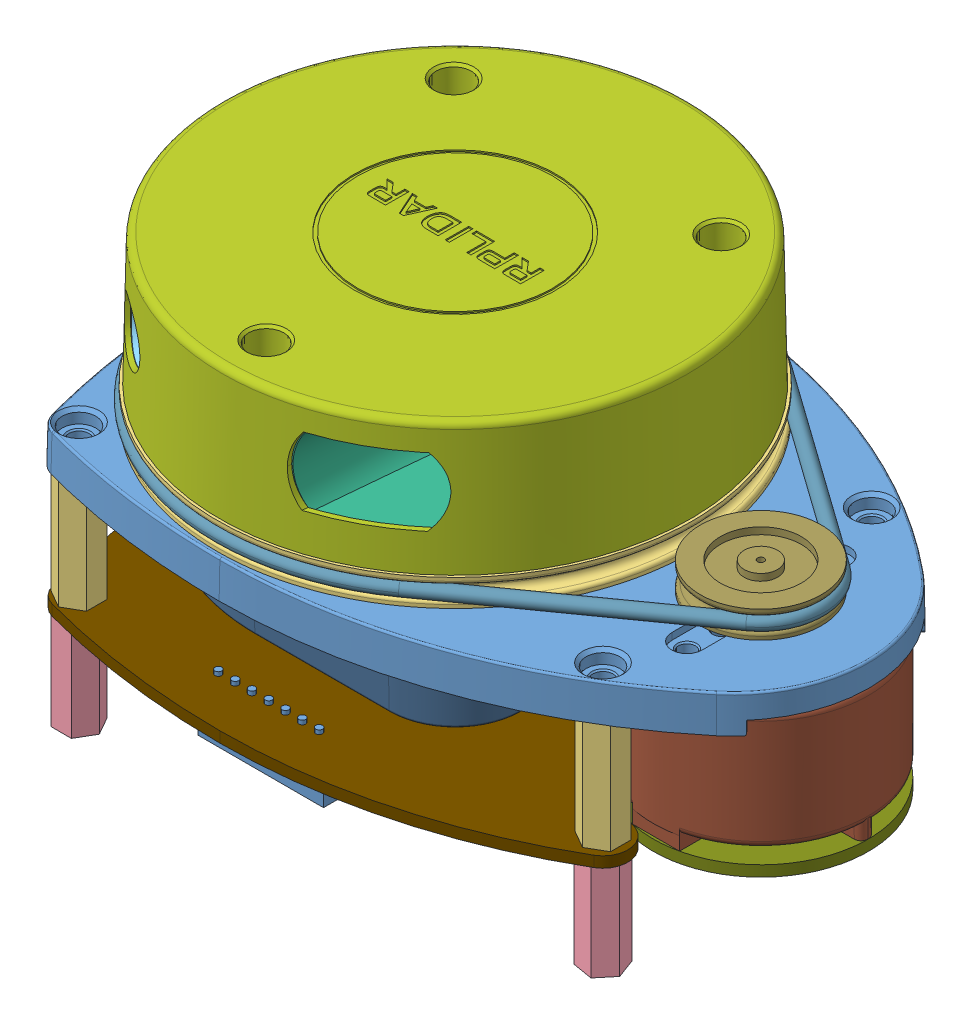
SolidWorks assembly LIDAR, configuration По умолчанию. Lengths in mm.
Overall size (102.81 63.21 71.78).
28 component instances, 22 part files, 30 mates.
Components (placement in the parent):
- 1-1: 1 [По умолчанию] at (-69.4738 21.696 -13.0661) size (96.74 12.71 70.28)
- 2-1: 2 [По умолчанию] at (-69.4738 23.696 -13.0661) x (1 0 0) z (0 -1 0) size (47 47 7.01)
- 3-1: 3 [По умолчанию] at (-69.4738 25.696 -13.0661) x (0.00451 0 -0.99999) z (0.99999 0 0.00451) size (70.79 21.41 70.79)
- 4-1: 4 [По умолчанию] at (-94.6291 38.696 -19.9402) x (0.990886 0 -0.134705) z (0.134705 0 0.990886) size (6.5 6.5 21.2)
- 5-1: 5 [По умолчанию] at (-69.4738 29.696 -13.0661) x (-0.99999 0 -0.00451) z (0.00451 0 -0.99999) size (15.26 18.52 21.56)
- 6-1: 6 [По умолчанию] at (-69.4738 29.696 -13.0661) x (-0.99999 0 -0.00451) z (0.00451 0 -0.99999) size (22.09 18.86 24.76)
- 7-1: 7 [По умолчанию] at (-69.4738 47.696 -13.0661) x (0.99999 0 0.00451) z (0.00451 0 -0.99999) size (70 19.51 70)
- 8-1: 8 [По умолчанию] at (-69.4738 12.696 -13.0661) x (0.987093 0 -0.160146) z (0.160146 0 0.987093) size (25 1.2 25)
- 9-1: 9 [По умолчанию] at (-69.4738 11.696 -13.0661) size (55.5 1 57)
- 10-1: 10 [По умолчанию] at (-69.4738 10.696 -13.0661) size (59.96 11.11 60.96)
- 11-1: 11 [По умолчанию] at (-23.9738 2.196 -13.0661) x (0 0 -1) z (1 0 0) size (32 30.21 32.01)
- 12-1: 12 [По умолчанию] at (-23.9738 24.196 -13.0661) x (0.135455 0 -0.990784) z (0.990784 0 0.135455) size (18 5.5 18)
- 13-1: 13 [По умолчанию] at (-52.5259 38.696 -1.4895) x (0.136926 0.990581 0.000618) z (-0.00451 0 0.99999) size (14 14 11.5)
- 14-1: 14 [По умолчанию] at (-69.4738 26.196 -13.0661) x (1 0 0) z (0 -1 0) size (90.89 71.78 2)
- 15-1: 15 [По умолчанию] at (-45.3638 9.296 -13.0661) x (0 0 -1) z (0 -1 0) size (10.15 4.2 4.7)
- 16-1: 16 [По умолчанию] at (-23.9738 -1.404 -13.0661) x (-0.441218 0 -0.8974) z (0.8974 0 -0.441218) size (32 1.6 32)
- 17-1: 17 [По умолчанию] at (-36.9138 -3.104 -13.0661) x (0 0 1) z (0 -1 0) size (8.9 5.2 3.4)
- 19-1: 19 [По умолчанию] at (-69.4738 0.896 -13.0661) x (1 0 0) z (0 0 -1) size (80.7 4.7 70)
- 20-1: 20 [По умолчанию] at (-69.4738 -0.704 14.0339) x (0 -1 0) z (1 0 0) size (8.2 5 20)
- 22-1: 22 [По умолчанию] at (-51.7938 -0.804 -13.0661) x (0 0 1) z (1 0 0) size (8.8 4.7 4.36)
- STANDOFF_M3_16.8H-1: STANDOFF_M3_16.8H [По умолчанию] at (-97.4738 0.896 -41.0661) size (5.27 16.8 6.09)
- STANDOFF_M3_16.8H-2: STANDOFF_M3_16.8H [По умолчанию] at (-27.4738 0.896 6.9339) size (5.27 16.8 6.09)
- STANDOFF_M3_16.8H-3: STANDOFF_M3_16.8H [По умолчанию] at (-27.4738 0.896 -33.0661) size (5.27 16.8 6.09)
- STANDOFF_M3_16.8H-4: STANDOFF_M3_16.8H [По умолчанию] at (-97.4738 0.896 14.9339) size (5.27 16.8 6.09)
- STANDOFF_M3_14.8H-4: STANDOFF_M3_14.8H [По умолчанию] at (-97.4738 -15.504 14.9339) x (0.868815 0 -0.495137) z (0.495137 0 0.868815) size (5.27 14.8 6.09)
- STANDOFF_M3_14.8H-5: STANDOFF_M3_14.8H [По умолчанию] at (-97.4738 -15.504 -41.0661) x (0.812883 0 -0.582428) z (0.582428 0 0.812883) size (5.27 14.8 6.09)
- STANDOFF_M3_14.8H-3: STANDOFF_M3_14.8H [По умолчанию] at (-27.4738 -15.504 -33.0661) x (0.760744 0 -0.649052) z (0.649052 0 0.760744) size (5.27 14.8 6.09)
- STANDOFF_M3_14.8H-6: STANDOFF_M3_14.8H [По умолчанию] at (-27.4738 -15.504 6.9339) x (-0.167625 0 0.985851) z (-0.985851 0 -0.167625) size (5.27 14.8 6.09)
Mates (geometry in assembly coordinates):
- Концентричный1: concentric anti-aligned: cylinder of 19-1 through (-76.9738 -0.704 14.6839) axis (0 1 0) radius 0.5; cylinder of 20-1 through (-76.9738 -0.704 14.6839) axis (0 -1 0) radius 0.5
- Концентричный2: concentric anti-aligned: cylinder of 19-1 through (-61.9738 -0.704 14.6839) axis (0 1 0) radius 0.5; cylinder of 20-1 through (-61.9738 -0.704 14.6839) axis (0 -1 0) radius 0.5
- Совпадение1: coincident anti-aligned: plane of 19-1 through (-83.4738 -0.704 10.2631) normal (0 -1 0); plane of 20-1 through (-69.4738 -0.704 14.0339) normal (0 1 0)
- Концентричный3: concentric aligned: cylinder of 1-1 through (-97.4738 20.996 14.9339) axis (0 -1 0) radius 1.5; cylinder of STANDOFF_M3_16.8H-4 through (-97.4738 17.696 14.9339) axis (0 -1 0) radius 1.5
- Концентричный4: concentric aligned: cylinder of 1-1 through (-97.4738 20.996 -41.0661) axis (0 -1 0) radius 1.5; cylinder of STANDOFF_M3_16.8H-1 through (-97.4738 17.696 -41.0661) axis (0 -1 0) radius 1.5
- Концентричный5: concentric aligned: cylinder of 1-1 through (-27.4738 20.996 6.9339) axis (0 -1 0) radius 1.5; cylinder of STANDOFF_M3_16.8H-2 through (-27.4738 17.696 6.9339) axis (0 -1 0) radius 1.5
- Концентричный6: concentric aligned: cylinder of 1-1 through (-27.4738 20.996 -33.0661) axis (0 -1 0) radius 1.5; cylinder of STANDOFF_M3_16.8H-3 through (-27.4738 17.696 -33.0661) axis (0 -1 0) radius 1.5
- Совпадение2: coincident anti-aligned: plane of 1-1 through (-69.4738 17.696 49.2172) normal (0 -1 0); plane of STANDOFF_M3_16.8H-4 through (-97.4738 17.696 14.9339) normal (0 1 0)
- Совпадение3: coincident anti-aligned: plane of 1-1 through (-69.4738 17.696 49.2172) normal (0 -1 0); plane of STANDOFF_M3_16.8H-1 through (-97.4738 17.696 -41.0661) normal (0 1 0)
- Совпадение4: coincident anti-aligned: plane of 1-1 through (-69.4738 17.696 49.2172) normal (0 -1 0); plane of STANDOFF_M3_16.8H-2 through (-27.4738 17.696 6.9339) normal (0 1 0)
- Совпадение5: coincident anti-aligned: plane of 1-1 through (-69.4738 17.696 49.2172) normal (0 -1 0); plane of STANDOFF_M3_16.8H-3 through (-27.4738 17.696 -33.0661) normal (0 1 0)
- Концентричный7: concentric anti-aligned: cylinder of 19-1 through (-27.4738 -0.704 6.9339) axis (0 1 0) radius 1.3; cylinder of STANDOFF_M3_16.8H-2 through (-27.4738 17.696 6.9339) axis (0 -1 0) radius 1.5
- Концентричный8: concentric anti-aligned: cylinder of 19-1 through (-97.4738 -0.704 14.9339) axis (0 1 0) radius 1.3; cylinder of STANDOFF_M3_16.8H-4 through (-97.4738 17.696 14.9339) axis (0 -1 0) radius 1.5
- Совпадение6: coincident anti-aligned: plane of 19-1 through (-83.4738 0.896 10.2631) normal (0 1 0); plane of STANDOFF_M3_16.8H-4 through (-97.4738 0.896 14.9339) normal (0 -1 0)
- Совпадение7: coincident anti-aligned: plane of 19-1 through (-69.4738 -0.804 -13.0661) normal (0 -1 0); plane of 22-1 through (-51.7938 -0.804 -13.0661) normal (0 1 0)
- Совпадение8: coincident aligned: plane of 19-1 through (-53.4738 -0.804 -17.4661) normal (-1 0 0); plane of 22-1 through (-53.4738 -5.504 -15.8161) normal (-1 0 0)
- Совпадение9: coincident: line of 19-1 through (-53.4738 -0.804 -8.6661) axis (1 0 0); plane of 22-1 through (-56.0583 -1.104 -8.6661) normal (0 0 1)
- Концентричный9: concentric aligned: cylinder of 1-1 through (-23.9738 19.696 -2.0661) axis (0 1 0) radius 1.25; cylinder of 11-1 through (-23.9738 15.696 -2.0661) axis (0 1 0) radius 1
- Концентричный10: concentric aligned: cylinder of 1-1 through (-23.9738 19.696 -24.0661) axis (0 1 0) radius 1.25; cylinder of 11-1 through (-23.9738 15.696 -24.0661) axis (0 1 0) radius 1
- Концентричный11: concentric anti-aligned: cylinder of 11-1 through (-23.9738 0.196 -13.0661) axis (0 1 0) radius 3.5; cylinder of 16-1 through (-23.9738 0.196 -13.0661) axis (0 -1 0) radius 3.75
- Совпадение10: coincident anti-aligned: plane of 11-1 through (-23.9738 0.196 -13.0661) normal (0 -1 0); plane of 16-1 through (-23.9738 0.196 -13.0661) normal (0 1 0)
- Совпадение11: coincident anti-aligned: plane of 1-1 through (-69.4738 19.696 -13.0661) normal (0 -1 0); plane of 11-1 through (-23.9738 19.696 -13.0661) normal (0 1 0)
- Концентричный12: concentric anti-aligned: cylinder of 19-1 through (-97.4738 -0.704 14.9339) axis (0 1 0) radius 1.3; cylinder of STANDOFF_M3_14.8H-4 through (-97.4738 -0.704 14.9339) axis (0 -1 0) radius 1.5
- Концентричный13: concentric anti-aligned: cylinder of 19-1 through (-97.4738 -0.704 -41.0661) axis (0 1 0) radius 1.3; cylinder of STANDOFF_M3_14.8H-5 through (-97.4738 -0.704 -41.0661) axis (0 -1 0) radius 1.5
- Концентричный14: concentric anti-aligned: cylinder of 19-1 through (-27.4738 -0.704 6.9339) axis (0 1 0) radius 1.3; cylinder of STANDOFF_M3_14.8H-6 through (-27.4738 -0.704 6.9339) axis (0 -1 0) radius 1.5
- Концентричный15: concentric anti-aligned: cylinder of 19-1 through (-27.4738 -0.704 -33.0661) axis (0 1 0) radius 1.3; cylinder of STANDOFF_M3_14.8H-3 through (-27.4738 -0.704 -33.0661) axis (0 -1 0) radius 1.5
- Совпадение12: coincident anti-aligned: plane of 19-1 through (-83.4738 -0.704 10.2631) normal (0 -1 0); plane of STANDOFF_M3_14.8H-5 through (-97.4738 -0.704 -41.0661) normal (0 1 0)
- Совпадение13: coincident anti-aligned: plane of 19-1 through (-83.4738 -0.704 10.2631) normal (0 -1 0); plane of STANDOFF_M3_14.8H-4 through (-97.4738 -0.704 14.9339) normal (0 1 0)
- Совпадение14: coincident anti-aligned: plane of 19-1 through (-83.4738 -0.704 10.2631) normal (0 -1 0); plane of STANDOFF_M3_14.8H-3 through (-27.4738 -0.704 -33.0661) normal (0 1 0)
- Совпадение15: coincident anti-aligned: plane of 19-1 through (-83.4738 -0.704 10.2631) normal (0 -1 0); plane of STANDOFF_M3_14.8H-6 through (-27.4738 -0.704 6.9339) normal (0 1 0)
